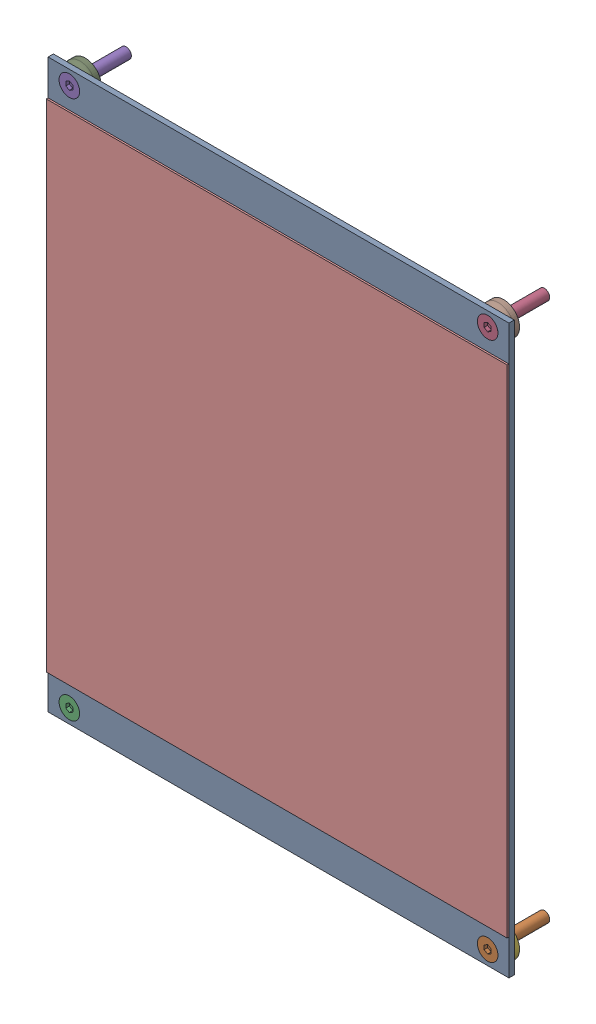
SolidWorks assembly Bed Surface_1.step, configuration Default. Lengths in mm.
Overall size (130 161 16.5).
20 component instances, 4 part files, 0 mates.
Components (placement in the parent):
- Heatbed.step-1: Heatbed.step [Default] at origin size (130 160 1.5)
  - Heatbed_1.step-1: Heatbed_1.step [Default] at (-282 -0.0875 103.5875) size (130 160 1.5)
- Bed Level Screw.step-1: Bed Level Screw.step [Default] at (0 -95 0) size (5.8 5.8 16)
  - Bed Level Screw_4.step-1: Bed Level Screw_4.step [Default] at (-223 18.9125 89.0875) size (5.8 5.8 16)
- Bed Level Screw_1.step-1: Bed Level Screw_1.step [Default] at (0 -110 0) size (5.8 5.8 16)
  - Bed Level Screw_4.step-1: Bed Level Screw_4.step [Default] at (-341 33.9125 89.0875) size (5.8 5.8 16)
- Bed Level Screw_2.step-1: Bed Level Screw_2.step [Default] at (0 90 0) size (5.8 5.8 16)
  - Bed Level Screw_4.step-1: Bed Level Screw_4.step [Default] at (-223 -14.0875 89.0875) size (5.8 5.8 16)
- Bed Level Screw_3.step-1: Bed Level Screw_3.step [Default] at (0 100 0) size (5.8 5.8 16)
  - Bed Level Screw_4.step-1: Bed Level Screw_4.step [Default] at (-341 -24.0875 89.0875) size (5.8 5.8 16)
- Bed Spring Cap_4.step-1: Bed Spring Cap_4.step [Default] at (0 -130 0) size (9 9 3)
  - Bed Spring Cap_8.step-1: Bed Spring Cap_8.step [Default] at (-223 53.9125 103.5875) x (1 0 0) z (0 0 -1) size (9 9 3)
- Bed Spring Cap_5.step-1: Bed Spring Cap_5.step [Default] at (0 -120 0) size (9 9 3)
  - Bed Spring Cap_8.step-1: Bed Spring Cap_8.step [Default] at (-341 43.9125 103.5875) x (1 0 0) z (0 0 -1) size (9 9 3)
- Bed Spring Cap_6.step-1: Bed Spring Cap_6.step [Default] at (0 120 0) size (9 9 3)
  - Bed Spring Cap_8.step-1: Bed Spring Cap_8.step [Default] at (-223 -44.0875 103.5875) x (1 0 0) z (0 0 -1) size (9 9 3)
- Bed Spring Cap_7.step-1: Bed Spring Cap_7.step [Default] at (0 140 0) size (9 9 3)
  - Bed Spring Cap_8.step-1: Bed Spring Cap_8.step [Default] at (-341 -64.0875 103.5875) x (1 0 0) z (0 0 -1) size (9 9 3)
- Print Surface.step-1: Print Surface.step [Default] at (140 0 0) size (130 140 0.5)
  - Print Surface_1.step-1: Print Surface_1.step [Default] at (-422 -0.0875 105.0875) size (130 140 0.5)
